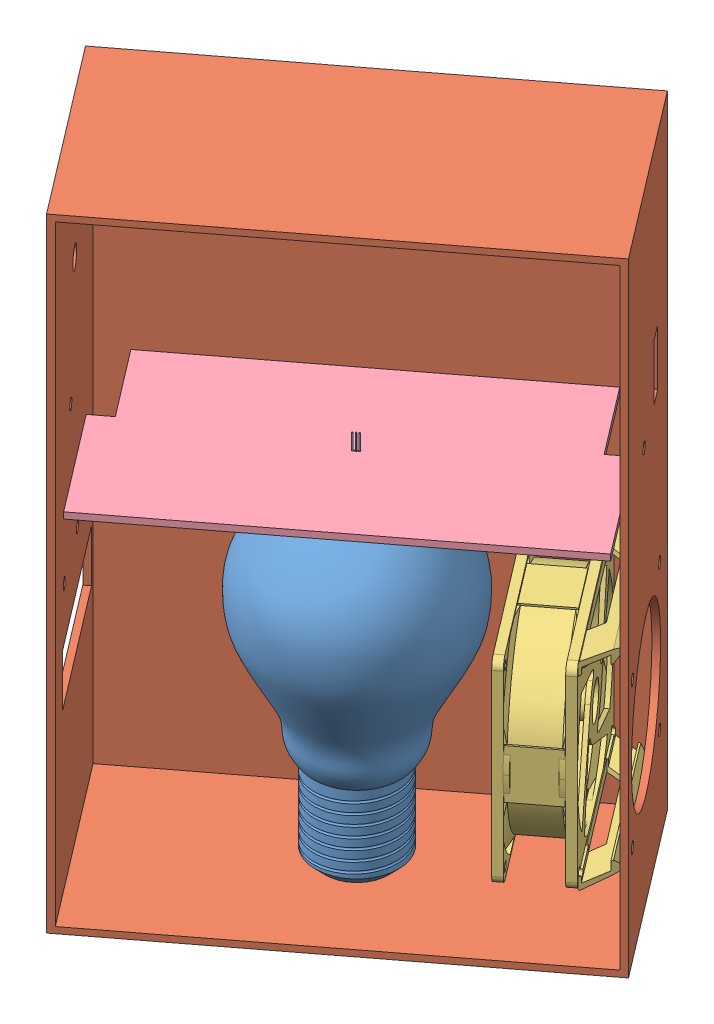
SolidWorks assembly Montagem4, configuration Valor predeterminado. Lengths in mm.
Overall size (219.64 300 200.88).
5 component instances, 5 part files, 11 mates.
Components (placement in the parent):
- bulb-1: bulb [Default] at (-95.926 -61.9878 159.1705) size (92.01 159.17 92.01)
- Caixa-1: Caixa [Valor predeterminado] at (-95.926 82.0122 159.1705) x (-0.79463 0 0.607095) z (0 1 0) size (200 100 300)
- FRAME OF BIG HEAT SINK FAN-3: FRAME OF BIG HEAT SINK FAN [Default] at (-38.8898 14.3921 121.8872) x (0.607095 0 0.79463) z (0 -1 0) size (94.43 43.76 95.55)
- suporte-1: suporte [Valor predeterminado] at (-64.9642 107.5122 199.6966) x (0.79463 0 -0.607095) z (0 -1 0) size (188 98 3)
- LM35DZ-2: LM35DZ [Default] at (-94.6221 101.1856 160.9551) x (-0.79463 0 0.607095) z (0.607095 0 0.79463) size (5.25 17.9 4.19)
Mates (geometry in assembly coordinates):
- Coincidente1: coincident: plane of assembly; plane of assembly; plane of Caixa-1 through (-124.4595 82.0122 121.8229) normal (0.607095 0 0.79463); plane of suporte-1 through (-57.7106 106.0122 70.8269) normal (-0.607095 0 -0.79463)
- Largura2: width: plane of assembly; plane of assembly; plane of assembly; plane of assembly; plane of suporte-1 through (9.731 106.0122 142.6297) normal (0.79463 0 -0.607095); plane of suporte-1 through (-139.6594 106.0122 256.7635) normal (-0.79463 0 0.607095); plane of Caixa-1 through (-201.5386 -64.9878 180.7111) normal (0.79463 0 -0.607095); plane of Caixa-1 through (-47.3804 -64.9878 62.9347) normal (-0.79463 0 0.607095)
- Concêntrico1: concentric: circle of assembly; circle of assembly; circle of bulb-1; circle of Caixa-1
- Coincidente2: coincident: plane of assembly; plane of assembly; plane of bulb-1 through (-95.926 -64.9878 159.1705) normal (0 -1 0); plane of Caixa-1 through (-47.3804 -64.9878 62.9347) normal (0 1 0)
- Distância2: distance = 120 mm: plane of assembly; plane of assembly; plane of suporte-1 through (-64.9642 109.0122 199.6966) normal (0 1 0); plane of Caixa-1 through (-47.3804 229.0122 62.9347) normal (0 -1 0)
- Paralelo1: parallel: plane of assembly; plane of assembly; plane of Caixa-1 through (-124.4595 82.0122 121.8229) normal (0.607095 0 0.79463); plane of LM35DZ-2 through (-93.6848 98.5856 158.7137) normal (-0.607095 0 -0.79463)
- Paralelo2: parallel: plane of assembly; plane of assembly; plane of Caixa-1 through (-47.3804 229.0122 62.9347) normal (0 -1 0); plane of LM35DZ-2 through (-94.6221 116.4856 160.9551) normal (0 1 0)
- Bloquear1: lock: unknown of suporte-1; unknown of LM35DZ-2
- Concêntrico2: concentric: circle of assembly; circle of assembly; circle of Caixa-1; circle of FRAME OF BIG HEAT SINK FAN-3
- Tangente1: tangent: plane of assembly; cylinder of assembly; plane of Caixa-1 through (-47.3804 -64.9878 62.9347) normal (-0.79463 0 0.607095); cylinder of FRAME OF BIG HEAT SINK FAN-3 through (21.9527 60.0058 154.5088) axis (-0.607095 0 -0.79463) radius 0.5
- Paralelo3: parallel: plane of assembly; plane of assembly; plane of FRAME OF BIG HEAT SINK FAN-3 through (-54.429 61.1421 118.8434) normal (0 1 0); plane of suporte-1 through (-64.9642 106.0122 199.6966) normal (0 -1 0)
